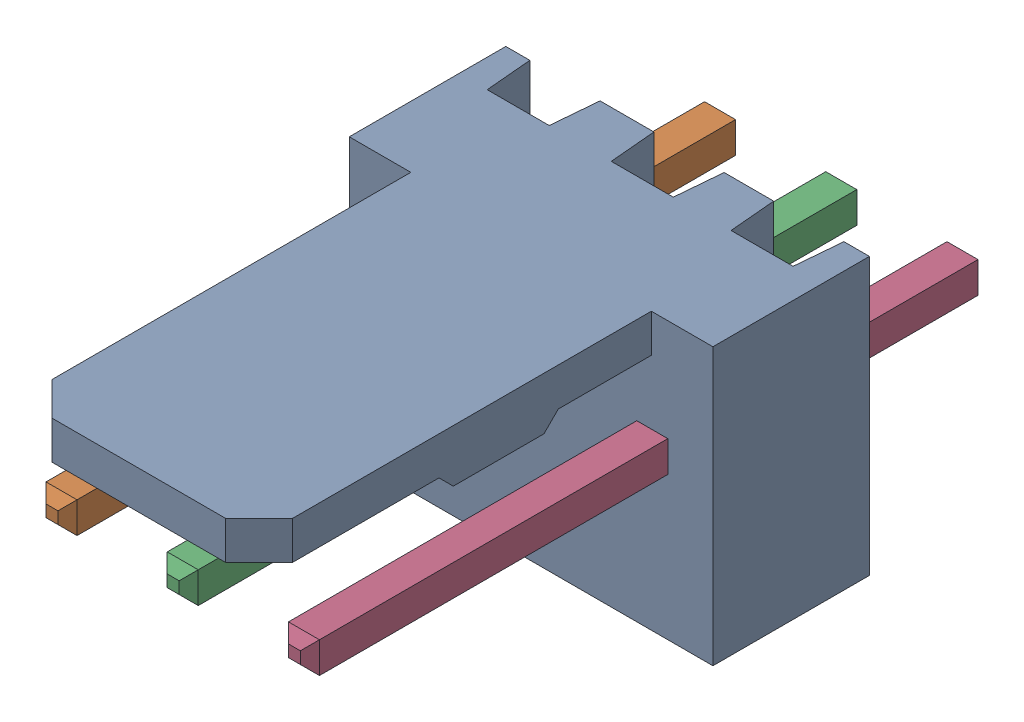
SolidWorks assembly Molex PCB 3 pin v2 v6_5, configuration Predeterminado. Lengths in mm.
Overall size (7.62 5.79 14.92).
4 component instances, 2 part files, 0 mates.
Components (placement in the parent):
- BASE9710016_2-1: BASE9710016_2 [Predeterminado] at (2.54 2.895 -8.22) size (7.62 5.79 11.5)
- PINO9710016_2-1: PINO9710016_2 [Predeterminado] at (1.27 3.325 -0.72) size (0.65 0.65 14.2)
- PINO9710016_2-2: PINO9710016_2 [Predeterminado] at (3.81 3.325 -0.72) size (0.65 0.65 14.2)
- PINO9710016_2-3: PINO9710016_2 [Predeterminado] at (6.35 3.325 -0.72) size (0.65 0.65 14.2)
